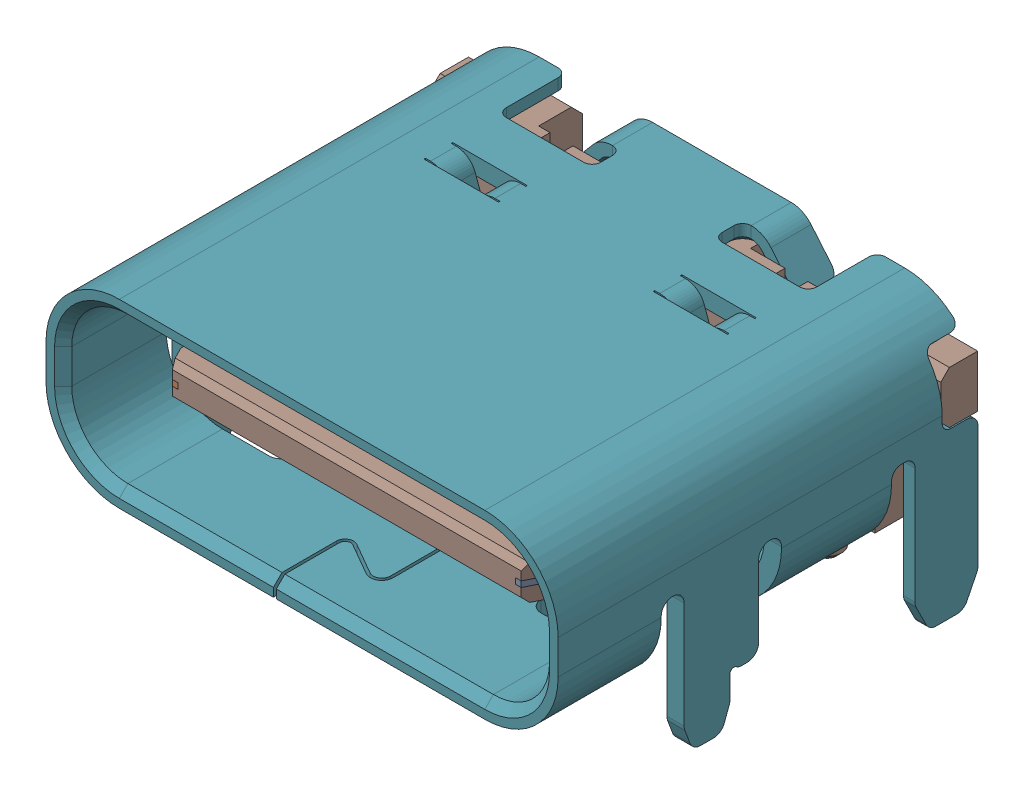
SolidWorks assembly Body_1_5, configuration Predeterminado. Lengths in mm.
Overall size (8.94 4.41 7.71).
45 component instances, 44 part files, 0 mates.
Components (placement in the parent):
- Imported_2-1: Imported_2 [Predeterminado] at (0 0 -1.255) size (8.94 4.41 7.71)
  - SOLID_41-1: SOLID_41 [Predeterminado] at origin size (0.25 0.05 2.38)
  - SOLID_42-1: SOLID_42 [Predeterminado] at origin size (0.25 0.05 2.38)
  - SOLID_43-1: SOLID_43 [Predeterminado] at origin size (0.25 0.05 1.88)
  - SOLID_44-1: SOLID_44 [Predeterminado] at origin size (0.25 0.05 1.88)
  - SOLID_45-1: SOLID_45 [Predeterminado] at origin size (0.25 0.05 1.88)
  - SOLID_46-1: SOLID_46 [Predeterminado] at origin size (0.25 0.05 1.88)
  - SOLID_47-1: SOLID_47 [Predeterminado] at origin size (0.25 0.05 1.88)
  - SOLID_48-1: SOLID_48 [Predeterminado] at origin size (0.25 0.05 1.88)
  - SOLID_49-1: SOLID_49 [Predeterminado] at origin size (0.25 0.05 1.88)
  - SOLID_50-1: SOLID_50 [Predeterminado] at origin size (0.25 0.05 1.88)
  - SOLID_51-1: SOLID_51 [Predeterminado] at origin size (0.25 0.05 2.38)
  - SOLID_52-1: SOLID_52 [Predeterminado] at origin size (0.25 0.05 2.38)
  - SOLID_53-1: SOLID_53 [Predeterminado] at origin size (0.25 0.05 2.38)
  - SOLID_54-1: SOLID_54 [Predeterminado] at origin size (0.25 0.05 1.88)
  - SOLID_55-1: SOLID_55 [Predeterminado] at origin size (0.25 0.05 1.88)
  - SOLID_56-1: SOLID_56 [Predeterminado] at origin size (0.25 0.05 2.38)
  - SOLID_57-1: SOLID_57 [Predeterminado] at origin size (0.25 0.05 1.88)
  - SOLID_58-1: SOLID_58 [Predeterminado] at origin size (0.25 0.05 1.88)
  - SOLID_59-1: SOLID_59 [Predeterminado] at origin size (0.25 0.05 1.88)
  - SOLID_60-1: SOLID_60 [Predeterminado] at origin size (0.25 0.05 1.88)
  - SOLID_61-1: SOLID_61 [Predeterminado] at origin size (0.25 0.05 2.38)
  - SOLID_62-1: SOLID_62 [Predeterminado] at origin size (0.25 0.05 1.88)
  - SOLID_63-1: SOLID_63 [Predeterminado] at origin size (0.25 0.05 1.88)
  - SOLID_64-1: SOLID_64 [Predeterminado] at origin size (0.25 0.05 2.38)
  - SOLID_65-1: SOLID_65 [Predeterminado] at origin size (0.35 0.1 1.82)
  - SOLID_66-1: SOLID_66 [Predeterminado] at origin size (0.35 0.1 1.82)
  - SOLID_67-1: SOLID_67 [Predeterminado] at origin size (0.2 0.32 0.73)
  - SOLID_68-1: SOLID_68 [Predeterminado] at origin size (0.2 0.32 0.73)
  - SOLID_69-1: SOLID_69 [Predeterminado] at origin size (0.2 0.32 0.73)
  - SOLID_70-1: SOLID_70 [Predeterminado] at origin size (0.2 0.32 0.73)
  - SOLID_71-1: SOLID_71 [Predeterminado] at origin size (0.2 0.32 0.73)
  - SOLID_72-1: SOLID_72 [Predeterminado] at origin size (0.2 0.32 0.73)
  - SOLID_73-1: SOLID_73 [Predeterminado] at origin size (0.2 0.32 0.73)
  - SOLID_74-1: SOLID_74 [Predeterminado] at origin size (0.2 0.32 0.73)
  - SOLID_75-1: SOLID_75 [Predeterminado] at origin size (0.2 0.32 0.73)
  - SOLID_76-1: SOLID_76 [Predeterminado] at origin size (0.2 0.32 0.73)
  - SOLID_77-1: SOLID_77 [Predeterminado] at origin size (0.2 0.32 0.73)
  - SOLID_78-1: SOLID_78 [Predeterminado] at origin size (0.2 0.32 0.73)
  - SOLID_79-1: SOLID_79 [Predeterminado] at origin size (0.2 0.32 0.73)
  - SOLID_80-1: SOLID_80 [Predeterminado] at origin size (0.2 0.32 0.73)
  - SOLID_81-1: SOLID_81 [Predeterminado] at origin size (0.2 0.32 0.73)
  - SOLID_82-1: SOLID_82 [Predeterminado] at origin size (0.2 0.32 0.73)
  - SOLID_83-1: SOLID_83 [Predeterminado] at origin size (8.94 4.41 7.34)
  - SOLID_84-1: SOLID_84 [Predeterminado] at origin size (8.89 3.61 6.57)
